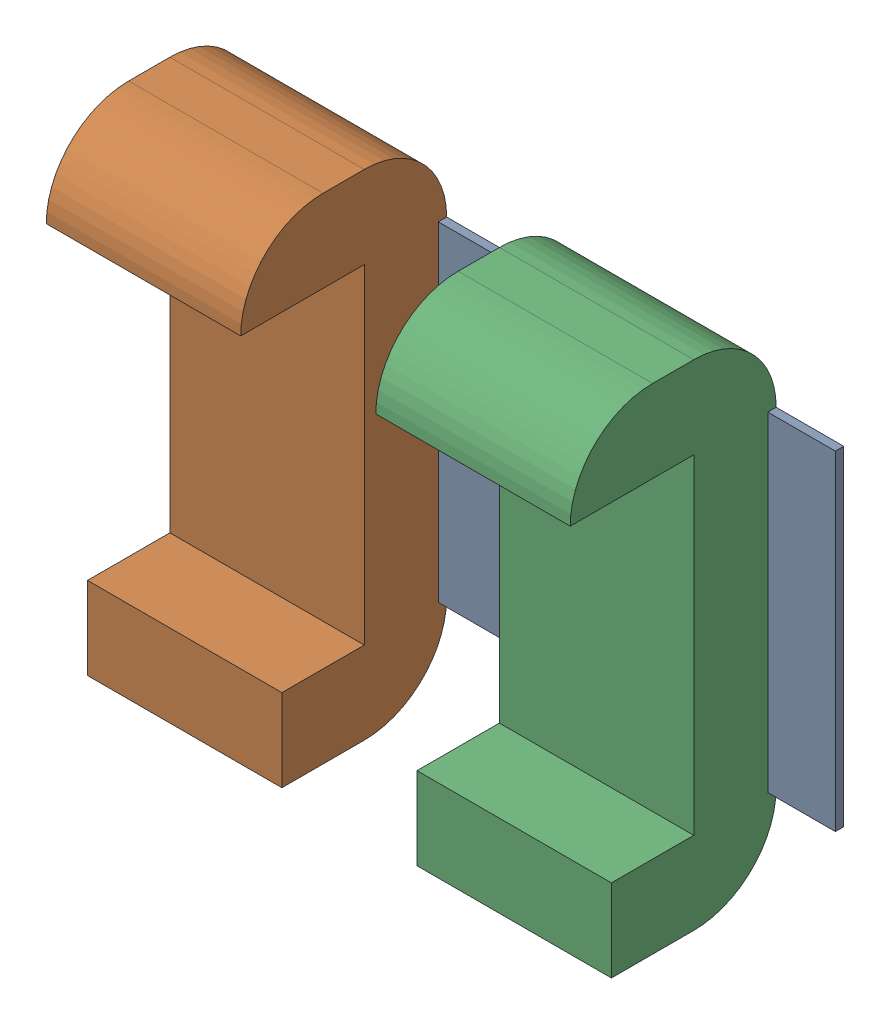
SolidWorks assembly Open CASCADE STEP translator 6.8 1.11.1, configuration Predeterminado. Lengths in mm.
Overall size (2 1.5 0.63).
3 component instances, 3 part files, 0 mates.
Components (placement in the parent):
- Body_1_4-1: Body_1_4 [Predeterminado] at origin size (2 1 0.03)
- Pin_1_3-1: Pin_1_3 [Predeterminado] x (0 1 0) z (0 0 1) size (1.5 0.59 0.63)
- Pin_2_3-1: Pin_2_3 [Predeterminado] at (1 -1 0) x (0 1 0) z (0 0 1) size (1.5 0.59 0.63)
